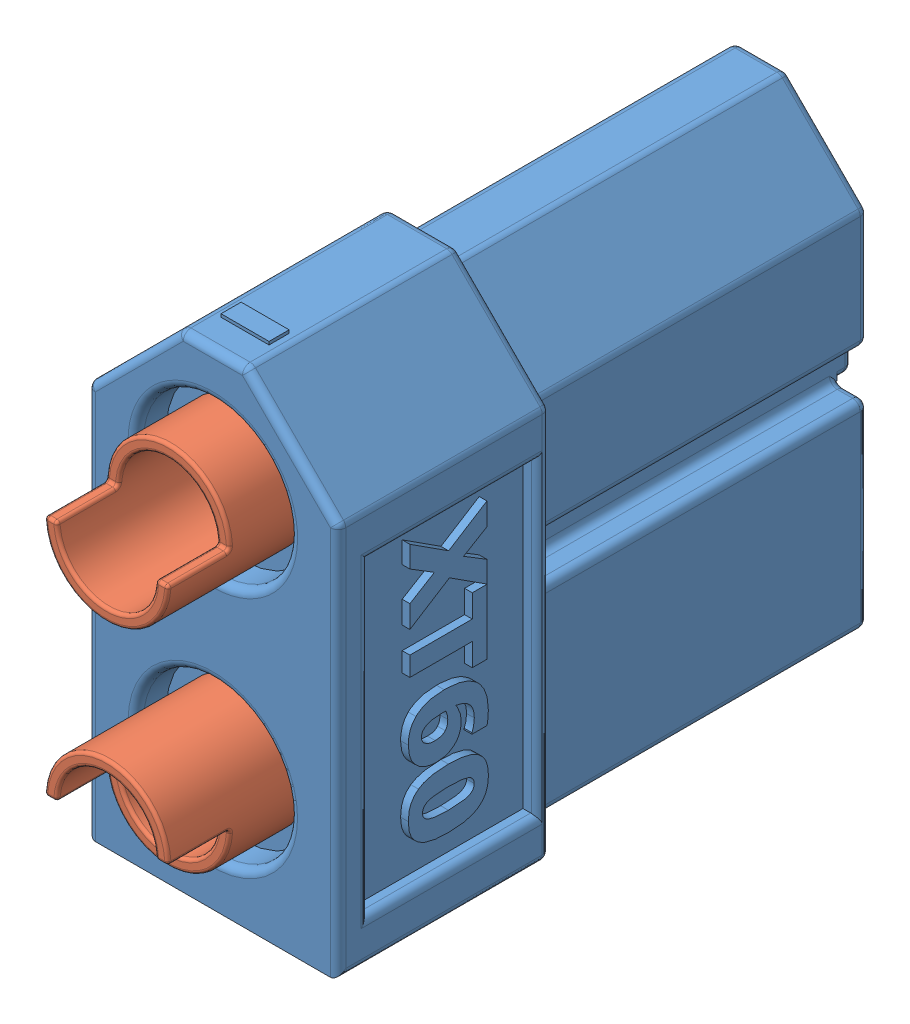
SolidWorks assembly XT60 Connector Female Connector, configuration Défaut. Lengths in mm.
Overall size (8.13 15.93 21.83).
3 component instances, 2 part files, 0 mates.
Components (placement in the parent):
- XT60 Connector Female Housing-1: XT60 Connector Female Housing [Défaut] at origin size (8.13 15.93 18.38)
- XT60 Connector Female Contact-1: XT60 Connector Female Contact [Défaut] at (4.064 3.934 39.207) x (1 0 0) z (0 0 -1) size (4 4 21.09)
- XT60 Connector Female Contact-2: XT60 Connector Female Contact [Défaut] at (4.064 11.801 39.207) x (-1 0 0) z (0 0 -1) size (4 4 21.09)
